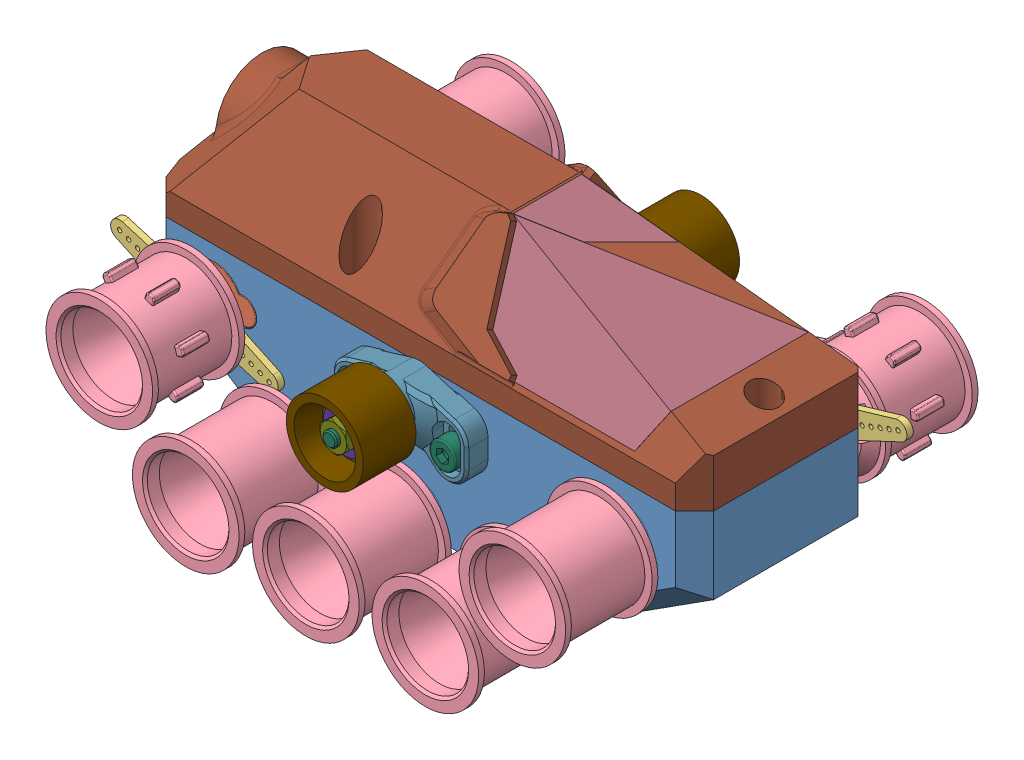
SolidWorks assembly bg_PipeMouse_Bodenwanne, configuration Standard. Lengths in mm.
Overall size (126.6 67.14 85.86).
80 component instances, 18 part files, 38 mates.
Components (placement in the parent):
- pipemouse_Bodenwanne-1: pipemouse_Bodenwanne [Standard] at (-4.1766 -19.3618 110) size (114 33.5 41.32)
- bg_PipeMouse_Antriebsstrang-1: bg_PipeMouse_Antriebsstrang [Standard] at (-24.1232 26.3288 110.494) x (1 0 0) z (0 -1 0) size (41.85 51.43 28.87)
  - BG_PipeMouse_Servo_SG90-1: BG_PipeMouse_Servo_SG90 [Standard] at (-17.0084 25.4339 -9.5058) size (38.93 31.63 40.07) (flexible)
    - pipemouse_Servo_SG90-1: pipemouse_Servo_SG90 [Standard] at (-11.8949 -15.4279 26.0464) size (32.2 30.3 12.3)
    - pipemouse_Servohorn_SG90-1: pipemouse_Servohorn_SG90 [Standard] at (-6.0449 16.2021 32.1964) x (0.934779 0 0.355229) z (0 -1 0) size (37.05 16.8 3.63)
  - pipemouse_KettenRad_v3-1: pipemouse_KettenRad_v3 [Kettenrad] at (-23.0534 51.836 22.6906) x (0.934779 0 0.355229) z (0 1 0) size (22.2 22.2 21.2)
- bg_PipeMouse_Antriebsstrang-2: bg_PipeMouse_Antriebsstrang [Standard] at (15.7701 26.3288 147.506) x (-1 0 0) z (0 -1 0) size (41.85 51.43 28.87)
  - BG_PipeMouse_Servo_SG90-1: BG_PipeMouse_Servo_SG90 [Standard] at (-17.0084 25.4339 -9.5058) size (38.93 31.63 40.07) (flexible)
    - pipemouse_Servo_SG90-1: pipemouse_Servo_SG90 [Standard] at (-11.8949 -15.4279 26.0464) size (32.2 30.3 12.3)
    - pipemouse_Servohorn_SG90-1: pipemouse_Servohorn_SG90 [Standard] at (-6.0449 16.2021 32.1964) x (0.934779 0 0.355229) z (0 -1 0) size (37.05 16.8 3.63)
  - pipemouse_KettenRad_v3-1: pipemouse_KettenRad_v3 [Kettenrad] at (-23.0534 51.836 22.6906) x (0.934779 0 0.355229) z (0 1 0) size (22.2 22.2 21.2)
- bg_PipeMouse_Laufrad-1: bg_PipeMouse_Laufrad [Standard] at (18.9362 -14.1612 117.87) x (-0.961576 -0.274538 0) z (0 0 -1) size (22.2 22.2 19.4)
  - pipemouse_KettenRad_v3-2: pipemouse_KettenRad_v3 [Standard] at (-2.0342 0.2506 22.2) size (22.2 22.2 19.2)
  - pipemouse_Kugellager_8x3x4-1: pipemouse_Kugellager_8x3x4 [Standard] at (-2.0342 0.2506 12.6) x (0.986697 0.162571 0) z (0 0 1) size (8 8 4)
  - pipemouse_U-Scheibe-1: pipemouse_U-Scheibe [Standard] at (-2.0342 0.2506 12.6) x (1 0 0) z (0 1 0) size (6.4 0.2 6.4)
  - pipemouse_U-Scheibe-2: pipemouse_U-Scheibe [Standard] at (-2.0342 0.2506 19.6) x (-0.923728 -0.383049 0) z (-0.383049 0.923728 0) size (6.4 0.2 6.4)
- bg_PipeMouse_Laufrad-2: bg_PipeMouse_Laufrad [Standard] at (-6.1637 -13.8641 117.87) x (-0.992196 -0.12469 0) z (0 0 -1) size (22.2 22.2 19.4)
  - pipemouse_KettenRad_v3-2: pipemouse_KettenRad_v3 [Standard] at (-2.0342 0.2506 22.2) size (22.2 22.2 19.2)
  - pipemouse_Kugellager_8x3x4-1: pipemouse_Kugellager_8x3x4 [Standard] at (-2.0342 0.2506 12.6) x (0.986697 0.162571 0) z (0 0 1) size (8 8 4)
  - pipemouse_U-Scheibe-1: pipemouse_U-Scheibe [Standard] at (-2.0342 0.2506 12.6) x (1 0 0) z (0 1 0) size (6.4 0.2 6.4)
  - pipemouse_U-Scheibe-2: pipemouse_U-Scheibe [Standard] at (-2.0342 0.2506 19.6) x (-0.923728 -0.383049 0) z (-0.383049 0.923728 0) size (6.4 0.2 6.4)
- bg_PipeMouse_Laufrad-3: bg_PipeMouse_Laufrad [Standard] at (-30.3396 -14.717 117.87) x (-0.764682 -0.644408 0) z (0 0 -1) size (22.2 22.2 19.4)
  - pipemouse_KettenRad_v3-2: pipemouse_KettenRad_v3 [Standard] at (-2.0342 0.2506 22.2) size (22.2 22.2 19.2)
  - pipemouse_Kugellager_8x3x4-1: pipemouse_Kugellager_8x3x4 [Standard] at (-2.0342 0.2506 12.6) x (0.986697 0.162571 0) z (0 0 1) size (8 8 4)
  - pipemouse_U-Scheibe-1: pipemouse_U-Scheibe [Standard] at (-2.0342 0.2506 12.6) x (1 0 0) z (0 1 0) size (6.4 0.2 6.4)
  - pipemouse_U-Scheibe-2: pipemouse_U-Scheibe [Standard] at (-2.0342 0.2506 19.6) x (-0.923728 -0.383049 0) z (-0.383049 0.923728 0) size (6.4 0.2 6.4)
- bg_PipeMouse_Laufrad-4: bg_PipeMouse_Laufrad [Standard] at (-27.3001 -14.1863 140.13) x (0.957843 -0.287291 0) z (0 0 1) size (22.2 22.2 19.4)
  - pipemouse_KettenRad_v3-2: pipemouse_KettenRad_v3 [Standard] at (-2.0342 0.2506 22.2) size (22.2 22.2 19.2)
  - pipemouse_Kugellager_8x3x4-1: pipemouse_Kugellager_8x3x4 [Standard] at (-2.0342 0.2506 12.6) x (0.986697 0.162571 0) z (0 0 1) size (8 8 4)
  - pipemouse_U-Scheibe-1: pipemouse_U-Scheibe [Standard] at (-2.0342 0.2506 12.6) x (1 0 0) z (0 1 0) size (6.4 0.2 6.4)
  - pipemouse_U-Scheibe-2: pipemouse_U-Scheibe [Standard] at (-2.0342 0.2506 19.6) x (-0.923728 -0.383049 0) z (-0.383049 0.923728 0) size (6.4 0.2 6.4)
- bg_PipeMouse_Laufrad-5: bg_PipeMouse_Laufrad [Standard] at (-2.1944 -13.8833 140.13) x (0.990943 -0.134282 0) z (0 0 1) size (22.2 22.2 19.4)
  - pipemouse_KettenRad_v3-2: pipemouse_KettenRad_v3 [Standard] at (-2.0342 0.2506 22.2) size (22.2 22.2 19.2)
  - pipemouse_Kugellager_8x3x4-1: pipemouse_Kugellager_8x3x4 [Standard] at (-2.0342 0.2506 12.6) x (0.986697 0.162571 0) z (0 0 1) size (8 8 4)
  - pipemouse_U-Scheibe-1: pipemouse_U-Scheibe [Standard] at (-2.0342 0.2506 12.6) x (1 0 0) z (0 1 0) size (6.4 0.2 6.4)
  - pipemouse_U-Scheibe-2: pipemouse_U-Scheibe [Standard] at (-2.0342 0.2506 19.6) x (-0.923728 -0.383049 0) z (-0.383049 0.923728 0) size (6.4 0.2 6.4)
- bg_PipeMouse_Laufrad-6: bg_PipeMouse_Laufrad [Standard] at (22.4194 -14.76 140.13) x (0.895692 -0.444675 0) z (0 0 1) size (22.2 22.2 19.4)
  - pipemouse_KettenRad_v3-2: pipemouse_KettenRad_v3 [Standard] at (-2.0342 0.2506 22.2) size (22.2 22.2 19.2)
  - pipemouse_Kugellager_8x3x4-1: pipemouse_Kugellager_8x3x4 [Standard] at (-2.0342 0.2506 12.6) x (0.986697 0.162571 0) z (0 0 1) size (8 8 4)
  - pipemouse_U-Scheibe-1: pipemouse_U-Scheibe [Standard] at (-2.0342 0.2506 12.6) x (1 0 0) z (0 1 0) size (6.4 0.2 6.4)
  - pipemouse_U-Scheibe-2: pipemouse_U-Scheibe [Standard] at (-2.0342 0.2506 19.6) x (-0.923728 -0.383049 0) z (-0.383049 0.923728 0) size (6.4 0.2 6.4)
- bg_PipeMouse_Laufrad-7: bg_PipeMouse_Laufrad [Standard] at (40.6945 2.8015 140.13) x (0.955953 -0.293521 0) z (0 0 1) size (22.2 22.2 19.4)
  - pipemouse_KettenRad_v3-2: pipemouse_KettenRad_v3 [Standard] at (-2.0342 0.2506 22.2) size (22.2 22.2 19.2)
  - pipemouse_Kugellager_8x3x4-1: pipemouse_Kugellager_8x3x4 [Standard] at (-2.0342 0.2506 12.6) x (0.986697 0.162571 0) z (0 0 1) size (8 8 4)
  - pipemouse_U-Scheibe-1: pipemouse_U-Scheibe [Standard] at (-2.0342 0.2506 12.6) x (1 0 0) z (0 1 0) size (6.4 0.2 6.4)
  - pipemouse_U-Scheibe-2: pipemouse_U-Scheibe [Standard] at (-2.0342 0.2506 19.6) x (-0.923728 -0.383049 0) z (-0.383049 0.923728 0) size (6.4 0.2 6.4)
- bg_PipeMouse_Laufrad-8: bg_PipeMouse_Laufrad [Standard] at (-48.9825 2.6689 117.87) x (-0.932322 -0.36163 0) z (0 0 -1) size (22.2 22.2 19.4)
  - pipemouse_KettenRad_v3-2: pipemouse_KettenRad_v3 [Standard] at (-2.0342 0.2506 22.2) size (22.2 22.2 19.2)
  - pipemouse_Kugellager_8x3x4-1: pipemouse_Kugellager_8x3x4 [Standard] at (-2.0342 0.2506 12.6) x (0.986697 0.162571 0) z (0 0 1) size (8 8 4)
  - pipemouse_U-Scheibe-1: pipemouse_U-Scheibe [Standard] at (-2.0342 0.2506 12.6) x (1 0 0) z (0 1 0) size (6.4 0.2 6.4)
  - pipemouse_U-Scheibe-2: pipemouse_U-Scheibe [Standard] at (-2.0342 0.2506 19.6) x (-0.923728 -0.383049 0) z (-0.383049 0.923728 0) size (6.4 0.2 6.4)
- socket head cap screw_iso-2: socket head cap screw_iso [ISO 4762 M3 x 20 - 20N] at (-4.1766 -13.3618 141) x (0 0 1) z (0.992401 -0.123045 0) size (23 5.5 5.5)
- plain washer normal grade a_iso-1: plain washer normal grade a_iso [Washer ISO 7089 - 3] at (-4.1766 -13.3618 150) x (0 0 1) z (-0.057183 0.998364 0) size (0.5 7 7)
- hex nut style 1 gradeab_iso-3: hex nut style 1 gradeab_iso [ISO - 4032 - M3 - D - N] at (-4.1766 -13.3618 150) x (0.858599 0.512649 0) z (0 0 -1) size (5.5 6.35 2.4)
- Lipo_HappyModell_2S_300mAh-1: Lipo_HappyModell_2S_300mAh [Standard] at (-34.1076 14.4612 136.7417) x (-0.001598 0 -0.999999) z (0.999999 0 -0.001598) size (15 17 55)
- pipemouse_WannenDeckel-1: pipemouse_WannenDeckel [Standard] at (-61.1766 12.6382 110) x (0 0 1) z (-1 0 0) size (39.38 25.64 114)
- cadxx_Turbo_Eon-1: cadxx_Turbo_Eon [Standard] at (-39.687 23.6382 129) x (0 0 -1) z (-1 0 0) size (14.15 16.25 16)
- pipemouse_Deckel-1: pipemouse_Deckel [Standard] at (-61.1766 12.6382 110.0683) x (0 0 1) z (-1 0 0) size (36.81 18.88 40.05)
- bg_Kettenspanner-2: bg_Kettenspanner [Standard] at (0.5367 6.3001 120) size (28 18.28 25.48) (flexible)
  - pipemouse_KettenspannerBlock-1: pipemouse_KettenspannerBlock [Standard] at (-4.7133 -1.8447 28) size (28 16.13 7)
  - socket head cap screw_din-1: socket head cap screw_din [DIN 912 M3 x 16 --- 16N] at (-4.7133 2.1553 28.1) x (0 0 1) z (-1 0 0) size (19 5.5 5.5)
  - hex nut style 1 gradeab_din-1: hex nut style 1 gradeab_din [Hexagon Nut ISO 4032 - M3 - W - N] at (-4.7133 2.1553 34.9) x (0.999968 0.007955 0) z (0 0 1) size (5.5 6.35 2.4)
  - plain washer large_din-1: plain washer large_din [Washer DIN 9021 - 3.2] at (-4.7133 2.1553 35) x (0 0 -1) z (1 0 0) size (0.8 9 9)
  - socket head cap screw_din-2: socket head cap screw_din [DIN 912 M3 x 8 --- 8N] at (-14.7133 -2.54 33.5) x (0 0 -1) z (0.996445 -0.084244 0) size (11 5.5 5.5)
  - socket head cap screw_din-3: socket head cap screw_din [DIN 912 M3 x 8 --- 8N] at (5.2867 -2.54 33.5) x (0 0 -1) z (0.996445 -0.084244 0) size (11 5.5 5.5)
  - pipemouse_KettenspannRad-1: pipemouse_KettenspannRad [Standard] at (-4.7133 2.1553 31.9828) x (0 0 1) z (-0.999376 0.035307 0) size (12 16 16)
  - pipemouse_Kugellager_8x3x4-1: pipemouse_Kugellager_8x3x4 [Standard] at (-4.7133 2.1553 39.9828) x (-1 0 0) z (0 0 -1) size (8 8 4)
  - plain washer large_din-2: plain washer large_din [Washer DIN 9021 - 3.2] at (-4.7133 2.1553 42.9828) x (0 0 -1) z (0.891573 -0.452878 0) size (0.8 9 9)
  - hex nut style 1 gradeab_din-2: hex nut style 1 gradeab_din [Hexagon Nut ISO 4032 - M3 - W - N] at (-4.7133 2.1553 46.1828) x (0.97662 0.214974 0) z (0 0 1) size (5.5 6.35 2.4)
- bg_Kettenspanner-3: bg_Kettenspanner [Standard] at (-8.8899 3.746 138) x (-1 0 0) z (0 0 -1) size (28 18.13 25.88) (flexible)
  - pipemouse_KettenspannerBlock-1: pipemouse_KettenspannerBlock [Standard] at (-4.7133 -1.8447 28) size (28 16.13 7)
  - socket head cap screw_din-1: socket head cap screw_din [DIN 912 M3 x 16 --- 16N] at (-4.7133 2.1553 28.1) x (0 0 1) z (-1 0 0) size (19 5.5 5.5)
  - hex nut style 1 gradeab_din-1: hex nut style 1 gradeab_din [Hexagon Nut ISO 4032 - M3 - W - N] at (-4.7133 2.1553 34.9) x (0.999968 0.007955 0) z (0 0 1) size (5.5 6.35 2.4)
  - plain washer large_din-1: plain washer large_din [Washer DIN 9021 - 3.2] at (-4.7133 2.1553 35) x (0 0 -1) z (1 0 0) size (0.8 9 9)
  - socket head cap screw_din-2: socket head cap screw_din [DIN 912 M3 x 8 --- 8N] at (-14.7133 0.1553 33.5) x (0 0 -1) z (0.996445 -0.084244 0) size (11 5.5 5.5)
  - socket head cap screw_din-3: socket head cap screw_din [DIN 912 M3 x 8 --- 8N] at (5.2867 0.1553 33.5) x (0 0 -1) z (0.996445 -0.084244 0) size (11 5.5 5.5)
  - pipemouse_KettenspannRad-1: pipemouse_KettenspannRad [Standard] at (-4.7133 2.1553 32.3753) x (0 0 1) z (-0.999872 -0.015969 0) size (12 16 16)
  - pipemouse_Kugellager_8x3x4-1: pipemouse_Kugellager_8x3x4 [Standard] at (-4.7133 2.1553 40.3753) x (-1 0 0) z (0 0 -1) size (8 8 4)
  - plain washer large_din-2: plain washer large_din [Washer DIN 9021 - 3.2] at (-4.7133 2.1553 43.3753) x (0 0 -1) z (0.891573 -0.452878 0) size (0.8 9 9)
  - hex nut style 1 gradeab_din-2: hex nut style 1 gradeab_din [Hexagon Nut ISO 4032 - M3 - W - N] at (-4.7133 2.1553 46.5753) x (0.97662 0.214974 0) z (0 0 1) size (5.5 6.35 2.4)
Mates (geometry in assembly coordinates):
- Konzentrisch1: concentric anti-aligned: cylinder of pipemouse_Bodenwanne-1 through (-47.1766 3.6382 148) axis (0 0 -1) radius 1.6; cylinder of bg_PipeMouse_Antriebsstrang-1/pipemouse_KettenRad_v3-1 through (-47.1766 3.6382 145.0589) axis (0 0 1) radius 2.5
- Konzentrisch2: concentric aligned: cylinder of pipemouse_Bodenwanne-1 through (38.8234 3.6382 148) axis (0 0 -1) radius 1.6; cylinder of bg_PipeMouse_Antriebsstrang-2/pipemouse_KettenRad_v3-1 through (38.8234 3.6382 131.8974) axis (0 0 -1) radius 1.25
- Konzentrisch3: concentric anti-aligned: cylinder of pipemouse_Bodenwanne-1 through (20.8234 -13.3618 148) axis (0 0 -1) radius 1.6; cylinder of bg_PipeMouse_Laufrad-1/pipemouse_Kugellager_8x3x4-1 through (20.8234 -13.3618 101.27) axis (0 0 1) radius 1.5
- Konzentrisch4: concentric anti-aligned: cylinder of pipemouse_Bodenwanne-1 through (-4.1766 -13.3618 148) axis (0 0 -1) radius 1.6; cylinder of bg_PipeMouse_Laufrad-2/pipemouse_Kugellager_8x3x4-1 through (-4.1766 -13.3618 101.27) axis (0 0 1) radius 1.5
- Konzentrisch5: concentric aligned: cylinder of bg_PipeMouse_Laufrad-4/pipemouse_Kugellager_8x3x4-1 through (-29.1766 -13.3618 156.73) axis (0 0 -1) radius 1.5; cylinder of pipemouse_Bodenwanne-1 through (-29.1766 -13.3618 148) axis (0 0 -1) radius 1.6
- Konzentrisch6: concentric aligned: cylinder of pipemouse_Bodenwanne-1 through (-4.1766 -13.3618 148) axis (0 0 -1) radius 1.6; cylinder of bg_PipeMouse_Laufrad-5/pipemouse_Kugellager_8x3x4-1 through (-4.1766 -13.3618 156.73) axis (0 0 -1) radius 1.5
- Konzentrisch7: concentric aligned: cylinder of bg_PipeMouse_Laufrad-7/pipemouse_Kugellager_8x3x4-1 through (38.8234 3.6382 156.73) axis (0 0 -1) radius 1.5; cylinder of pipemouse_Bodenwanne-1 through (38.8234 3.6382 148) axis (0 0 -1) radius 1.6
- Konzentrisch8: concentric anti-aligned: cylinder of pipemouse_Bodenwanne-1 through (-47.1766 3.6382 148) axis (0 0 -1) radius 1.6; cylinder of bg_PipeMouse_Laufrad-8/pipemouse_Kugellager_8x3x4-1 through (-47.1766 3.6382 101.27) axis (0 0 1) radius 1.5
- Konzentrisch10: concentric aligned: cylinder of pipemouse_Bodenwanne-1 through (-4.1766 -13.3618 148) axis (0 0 -1) radius 1.6; cylinder of socket head cap screw_iso-2 through (-4.1766 -13.3618 109.25) axis (0 0 -1) radius 2.75
- Deckungsgleich3: coincident anti-aligned: plane of pipemouse_Bodenwanne-1 through (-4.1766 -13.3618 144) normal (0 0 -1); plane of socket head cap screw_iso-2 through (-4.5149 -16.0909 144) normal (0 0 1)
- Deckungsgleich4: coincident aligned: plane of bg_PipeMouse_Antriebsstrang-1/pipemouse_KettenRad_v3-1 through (-47.1766 3.6382 153.93) normal (0 0 1); plane of bg_PipeMouse_Laufrad-5/pipemouse_KettenRad_v3-2 through (-4.1766 -13.3618 153.93) normal (0 0 1)
- Deckungsgleich5: coincident aligned: plane of bg_PipeMouse_Antriebsstrang-1/pipemouse_KettenRad_v3-1 through (-47.1766 3.6382 153.93) normal (0 0 1); plane of bg_PipeMouse_Laufrad-4/pipemouse_KettenRad_v3-2 through (-29.1766 -13.3618 153.93) normal (0 0 1)
- Deckungsgleich6: coincident aligned: plane of bg_PipeMouse_Antriebsstrang-1/pipemouse_KettenRad_v3-1 through (-47.1766 3.6382 153.93) normal (0 0 1); plane of bg_PipeMouse_Laufrad-6/pipemouse_KettenRad_v3-2 through (20.7088 -13.6309 153.93) normal (0 0 1)
- Deckungsgleich7: coincident aligned: plane of bg_PipeMouse_Antriebsstrang-1/pipemouse_KettenRad_v3-1 through (-47.1766 3.6382 153.93) normal (0 0 1); plane of bg_PipeMouse_Laufrad-7/pipemouse_KettenRad_v3-2 through (38.8234 3.6382 153.93) normal (0 0 1)
- Konzentrisch20: concentric aligned: cylinder of socket head cap screw_iso-2 through (-4.1766 -13.3618 109.25) axis (0 0 -1) radius 1.5; cylinder of plain washer normal grade a_iso-1 through (-4.1766 -13.3618 115.075) axis (0 0 -1) radius 1.6
- Deckungsgleich10: coincident anti-aligned: plane of pipemouse_Bodenwanne-1 through (-4.1766 -13.3618 149.5) normal (0 0 1); plane of plain washer normal grade a_iso-1 through (-0.6823 -13.1617 149.5) normal (0 0 -1)
- Konzentrisch21: concentric aligned: cylinder of socket head cap screw_iso-2 through (-4.1766 -13.3618 109.25) axis (0 0 -1) radius 1.5; cylinder of hex nut style 1 gradeab_iso-3 through (-4.1766 -13.3618 175.0375) axis (0 0 -1) radius 1.5
- Deckungsgleich11: coincident anti-aligned: plane of plain washer normal grade a_iso-1 through (-2.5792 -13.2703 150) normal (0 0 1); plane of hex nut style 1 gradeab_iso-3 through (-2.5487 -16.0882 150) normal (0 0 -1)
- Parallel2: parallel aligned: plane of pipemouse_Bodenwanne-1 through (-61.1766 12.6382 148) normal (0 1 0); plane of bg_PipeMouse_Antriebsstrang-2/BG_PipeMouse_Servo_SG90-1/pipemouse_Servo_SG90-1 through (44.6734 9.7882 137.5) normal (0 1 0)
- Parallel3: parallel aligned: plane of pipemouse_Bodenwanne-1 through (-61.1766 12.6382 148) normal (0 1 0); plane of bg_PipeMouse_Antriebsstrang-1/BG_PipeMouse_Servo_SG90-1/pipemouse_Servo_SG90-1 through (-53.0266 9.7882 120.5) normal (0 1 0)
- Deckungsgleich15: coincident aligned: plane of pipemouse_Bodenwanne-1 through (-4.1766 -19.3618 148) normal (0 0 1); plane of bg_PipeMouse_Antriebsstrang-1/BG_PipeMouse_Servo_SG90-1/pipemouse_Servo_SG90-1 through (-41.1766 3.6382 148) normal (0 0 1)
- Deckungsgleich16: coincident aligned: plane of pipemouse_Bodenwanne-1 through (-4.1766 -19.3618 110) normal (0 0 -1); plane of bg_PipeMouse_Antriebsstrang-2/BG_PipeMouse_Servo_SG90-1/pipemouse_Servo_SG90-1 through (32.8234 3.6382 110) normal (0 0 -1)
- Deckungsgleich20: coincident aligned: plane of bg_PipeMouse_Laufrad-2/pipemouse_KettenRad_v3-2 through (-4.1766 -13.3618 104.07) normal (0 0 -1); plane of bg_PipeMouse_Laufrad-3/pipemouse_KettenRad_v3-2 through (-28.9455 -13.2145 104.07) normal (0 0 -1)
- Deckungsgleich21: coincident aligned: plane of bg_PipeMouse_Laufrad-3/pipemouse_KettenRad_v3-2 through (-28.9455 -13.2145 104.07) normal (0 0 -1); plane of bg_PipeMouse_Laufrad-8/pipemouse_KettenRad_v3-2 through (-47.1766 3.6382 104.07) normal (0 0 -1)
- Parallel4: parallel aligned: plane of bg_PipeMouse_Antriebsstrang-2/BG_PipeMouse_Servo_SG90-1/pipemouse_Servo_SG90-1 through (44.6734 9.7882 137.5) normal (0 1 0); plane of Lipo_HappyModell_2S_300mAh-1 through (15.8923 31.4612 136.6618) normal (0 1 0)
- Deckungsgleich22: coincident anti-aligned: plane of pipemouse_Bodenwanne-1 through (-61.1766 12.6382 148) normal (0 1 0); plane of pipemouse_WannenDeckel-1 through (-61.1766 12.6382 148) normal (0 -1 0)
- Deckungsgleich23: coincident aligned: plane of pipemouse_Bodenwanne-1 through (-61.1766 -3.3618 148) normal (-1 0 0); plane of pipemouse_WannenDeckel-1 through (-61.1766 17.6382 148) normal (-1 0 0)
- Deckungsgleich24: coincident aligned: plane of pipemouse_Bodenwanne-1 through (-4.1766 -19.3618 148) normal (0 0 1); plane of pipemouse_WannenDeckel-1 through (-61.1766 12.6382 148) normal (0 0 1)
- Konzentrisch22: concentric anti-aligned: cylinder of pipemouse_WannenDeckel-1 through (52.8244 23.6382 129) axis (-1 0 0) radius 8; cylinder of cadxx_Turbo_Eon-1 through (-49.887 23.6382 129) axis (1 0 0) radius 6
- Parallel5: parallel anti-aligned: plane of pipemouse_Bodenwanne-1 through (-61.1766 12.6382 148) normal (0 1 0); plane of cadxx_Turbo_Eon-1 through (-41.587 16.5132 136.075) normal (0 -1 0)
- Deckungsgleich25: coincident anti-aligned: plane of pipemouse_WannenDeckel-1 through (3.2215 37.5188 109.99) normal (0.973176 0.230063 0); plane of pipemouse_Deckel-1 through (3.2215 37.5188 110.0583) normal (-0.973176 -0.230063 0)
- Deckungsgleich26: coincident anti-aligned: plane of pipemouse_WannenDeckel-1 through (6.7393 22.6382 109.99) normal (0.44348 0.896284 0); plane of pipemouse_Deckel-1 through (6.7393 22.6382 110.0583) normal (-0.44348 -0.896284 0)
- Deckungsgleich30: coincident anti-aligned: plane of pipemouse_Bodenwanne-1 through (-4.1766 -19.3618 148) normal (0 0 1); plane of bg_Kettenspanner-2/pipemouse_KettenspannerBlock-1 through (-4.1766 8.4554 148) normal (0 0 -1)
- Langloch1: slot anti-aligned: cylinder of bg_Kettenspanner-2/pipemouse_KettenspannerBlock-1 through (5.8234 2.4554 152.5) axis (0 0 -1) radius 1.6; cylinder of pipemouse_Bodenwanne-1 through (5.8234 3.6382 108.3378) axis (0 0 1) radius 1.55; cylinder of bg_Kettenspanner-2/pipemouse_KettenspannerBlock-1 through (5.8234 6.4554 152.5) axis (0 0 -1) radius 1.6
- Langloch2: slot anti-aligned: cylinder of bg_Kettenspanner-2/pipemouse_KettenspannerBlock-1 through (-14.1766 2.4554 152.5) axis (0 0 -1) radius 1.6; cylinder of pipemouse_Bodenwanne-1 through (-14.1766 3.6382 108.3378) axis (0 0 1) radius 1.55; cylinder of bg_Kettenspanner-2/pipemouse_KettenspannerBlock-1 through (-14.1766 6.4554 152.5) axis (0 0 -1) radius 1.6
- Deckungsgleich31: coincident anti-aligned: plane of pipemouse_Bodenwanne-1 through (-4.1766 -19.3618 110) normal (0 0 -1); plane of bg_Kettenspanner-3/pipemouse_KettenspannerBlock-1 through (-4.1766 5.9013 110) normal (0 0 1)
- Langloch3: slot aligned: cylinder of bg_Kettenspanner-3/pipemouse_KettenspannerBlock-1 through (-14.1766 -0.0987 105.5) axis (0 0 1) radius 1.6; cylinder of pipemouse_Bodenwanne-1 through (-14.1766 3.6382 108.3378) axis (0 0 1) radius 1.55; cylinder of bg_Kettenspanner-3/pipemouse_KettenspannerBlock-1 through (-14.1766 3.9013 105.5) axis (0 0 1) radius 1.6
- Langloch4: slot aligned: cylinder of bg_Kettenspanner-3/pipemouse_KettenspannerBlock-1 through (5.8234 -0.0987 105.5) axis (0 0 1) radius 1.6; cylinder of pipemouse_Bodenwanne-1 through (5.8234 3.6382 108.3378) axis (0 0 1) radius 1.55; cylinder of bg_Kettenspanner-3/pipemouse_KettenspannerBlock-1 through (5.8234 3.9013 105.5) axis (0 0 1) radius 1.6
